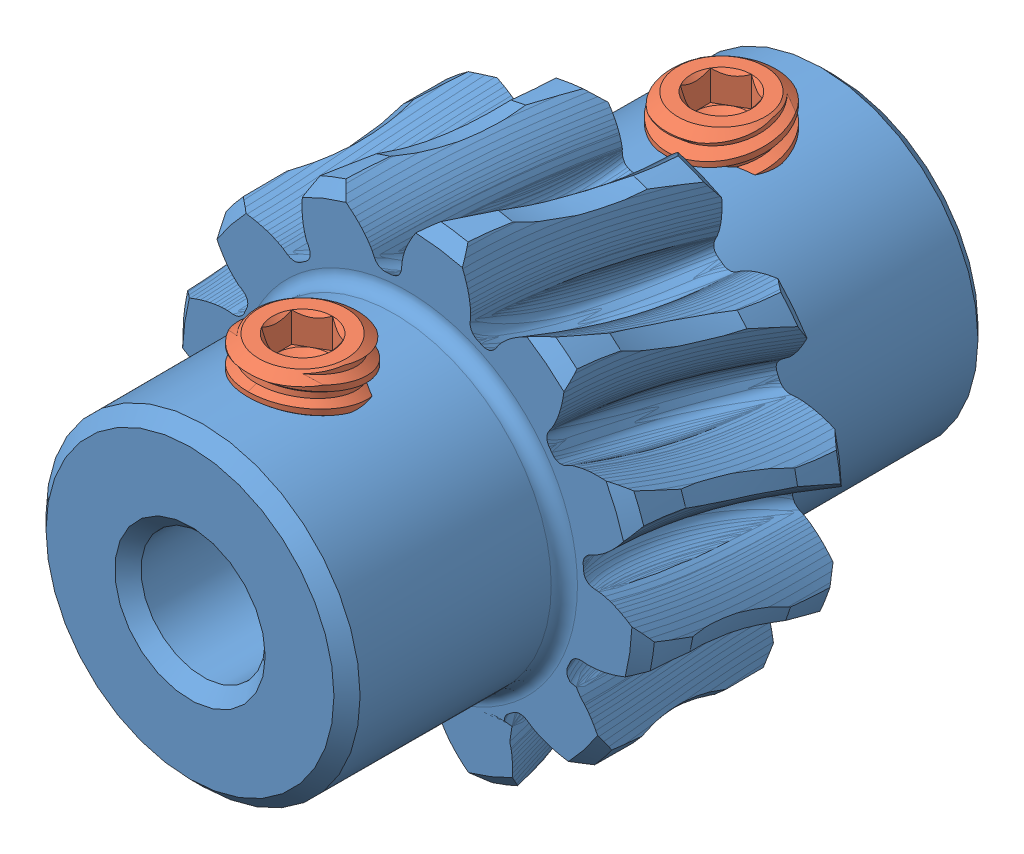
SolidWorks assembly Tetrix Worm Gear (4 to 1), configuration Default. Lengths in mm.
Overall size (19.96 19.96 24.6).
3 component instances, 2 part files, 0 mates.
Components (placement in the parent):
- Tetrix Worm Gear (4 to 1) Body-1: Tetrix Worm Gear (4 to 1) Body [Default] at origin size (19.96 19.96 24.6)
- Tetrix Worm (4 to 1) Set Screw-1: Tetrix Worm (4 to 1) Set Screw [Default] at (0 5.0448 -8) x (1 0 0) z (0 1 0) size (4.17 4.24 4.88)
- Tetrix Worm (4 to 1) Set Screw-2: Tetrix Worm (4 to 1) Set Screw [Default] at (0 5.0448 8) x (-1 0 0) z (0 1 0) size (4.17 4.24 4.88)
